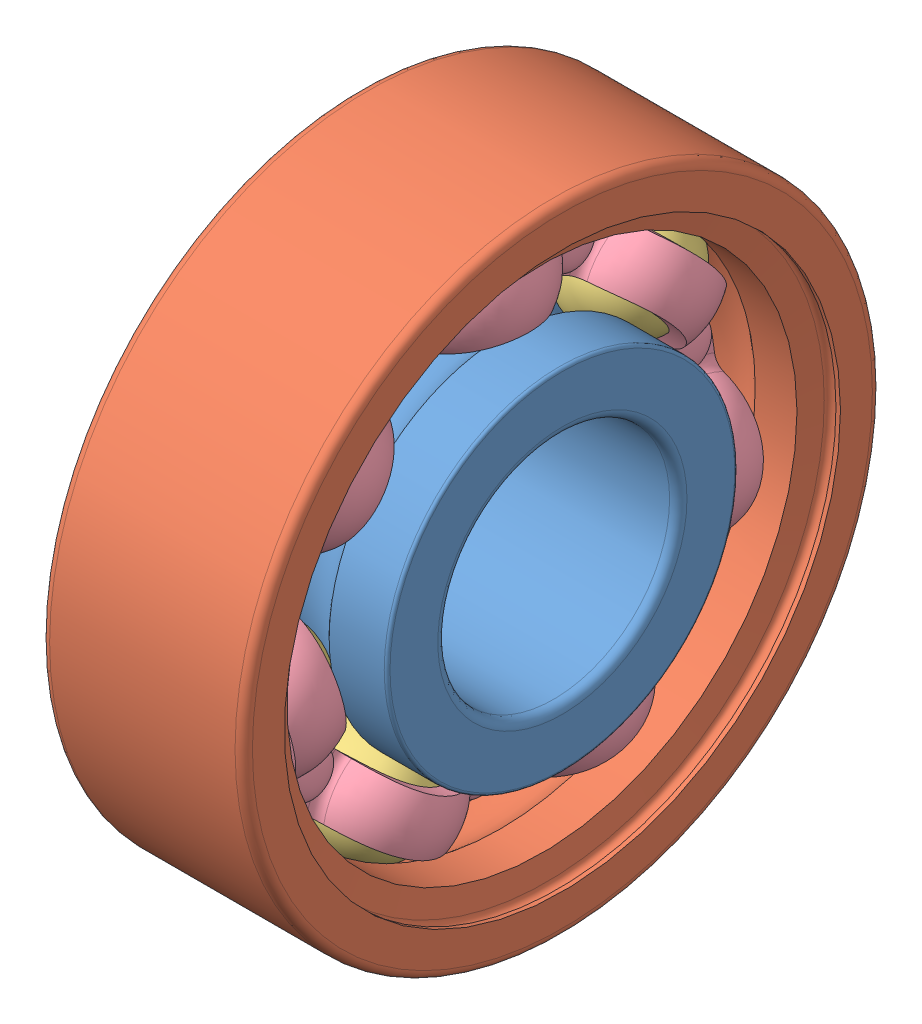
SolidWorks assembly 608, configuration SKF 608. Lengths in mm.
Overall size (7 22 22).
10 component instances, 4 part files, 4 mates.
Components (placement in the parent):
- 608 Inner Race^608-1: 608 Inner Race^608 [Default] at origin size (7 12.1 12.1) (virtual)
- 608 Outer Race^608-1: 608 Outer Race^608 [Default] at origin size (7 22 22) (virtual)
- 608 Ball^608-1: 608 Ball^608 [Default] at origin size (3.97 3.97 3.97) (virtual)
- 608 Ball^608-2: 608 Ball^608 [Default] x (1 0 0) z (0 -0.781831 0.62349) size (3.97 3.97 3.97) (virtual)
- 608 Ball^608-3: 608 Ball^608 [Default] x (1 0 0) z (0 -0.974928 -0.222521) size (3.97 3.97 3.97) (virtual)
- 608 Ball^608-4: 608 Ball^608 [Default] x (1 0 0) z (0 -0.433884 -0.900969) size (3.97 3.97 3.97) (virtual)
- 608 Ball^608-5: 608 Ball^608 [Default] x (1 0 0) z (0 0.433884 -0.900969) size (3.97 3.97 3.97) (virtual)
- 608 Ball^608-6: 608 Ball^608 [Default] x (1 0 0) z (0 0.974928 -0.222521) size (3.97 3.97 3.97) (virtual)
- 608 Ball^608-7: 608 Ball^608 [Default] x (1 0 0) z (0 0.781831 0.62349) size (3.97 3.97 3.97) (virtual)
- Ball retainer rings^608-1: Ball retainer rings^608 [Default] at (3.5 0 0) x (0 0 -1) z (1 0 0) size (16.6 16.6 4.97) (virtual)
Mates (geometry in assembly coordinates):
- InPlace1: in place: plane of Ball retainer rings^608-1 through (3.5 0 0) normal (1 0 0); moOrthogonalPlaneRef_w of Ball retainer rings^608-1 through (-55 3.5 0) axis (0 0 1); plane of Ball retainer rings^608-1 through (3.5 0 0) normal (0 0 -1); unknown of Ball retainer rings^608-1
- Coincident1: coincident aligned: plane of Ball retainer rings^608-1; plane of assembly
- Coincident2: coincident aligned: plane of Ball retainer rings^608-1; moOrthogonalPlaneRef_w of assembly
- Coincident3: coincident anti-aligned: plane of Ball retainer rings^608-1 through (3.5 0 0) normal (0 0 -1); moOrthogonalPlaneRef_w of assembly
